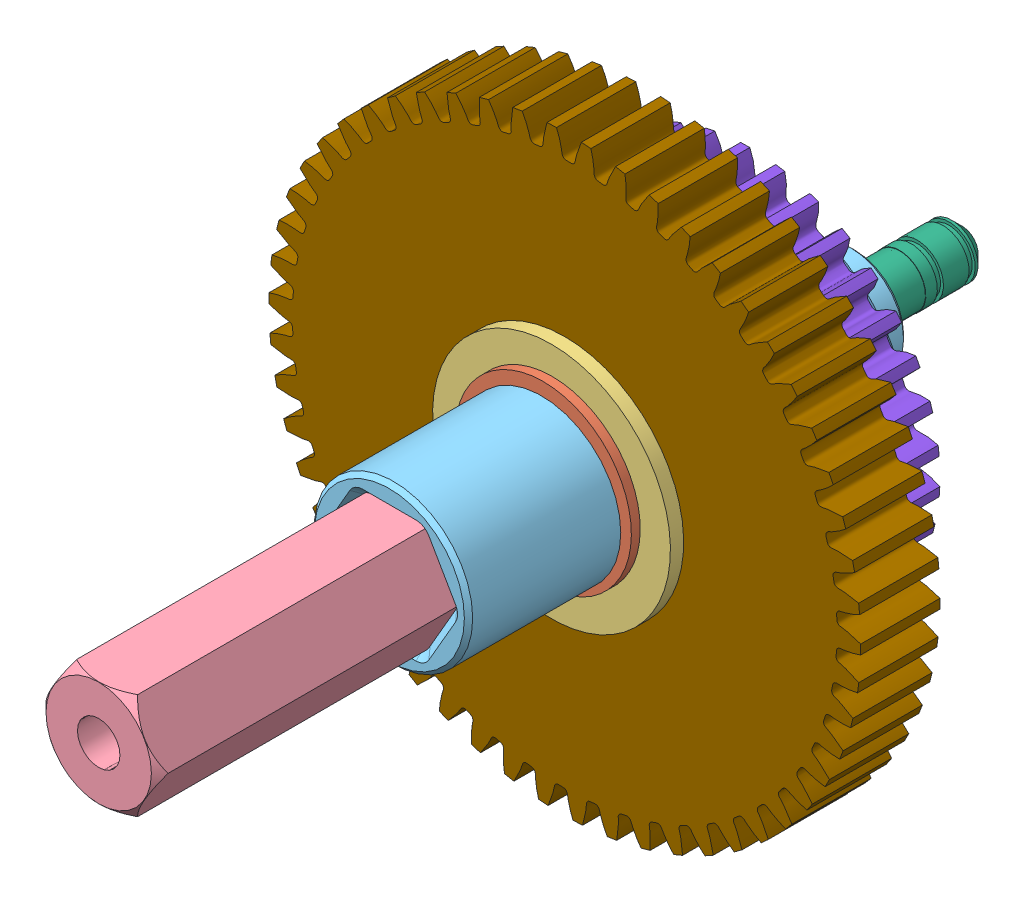
SolidWorks assembly 217-3291-STEP, configuration Default. Lengths in mm.
Overall size (93.31 93.34 103.75).
18 component instances, 9 part files, 0 mates.
Components (placement in the parent):
- 217-2428-008 Rev1-1: 217-2428-008 Rev1 [Default] at (0 0 10.2679) size (31.75 31.75 1.59)
- 217-2428-028 Rev1_97633A250-1: 217-2428-028 Rev1_97633A250 [Default] at (0 0 37.1221) x (0 0 1) z (0.9357 -0.352797 0) size (1.07 23.39 21.18)
- 217-2709-101 Rev1-1: 217-2709-101 Rev1 [Default] at (0 0 20.7137) x (-0.338464 -0.940979 0) z (0 0 -1) size (28.57 28.57 6.1)
  - 217-2428-022 Rev1-1: 217-2428-022 Rev1 [Default] at origin size (28.57 28.57 6.1)
- 217-2713-101 Rev1-1: 217-2713-101 Rev1 [Default] at (0 0 33.4137) x (0.847823 -0.530279 0) z (0 0 -1) size (28.57 28.57 6.1)
  - 217-2428-022 Rev1-1: 217-2428-022 Rev1 [Default] at origin size (28.57 28.57 6.1)
- 217-2790-001 Rev2-1: 217-2790-001 Rev2 [Default] x (-1 0 0) z (0 0 1) size (22.23 22.23 103.75)
  - 217-2790-002 Rev2-1: 217-2790-002 Rev2 [Default] at (0 0 62.9285) x (0 0 1) z (1 0 0) size (55.88 12.7 16.13)
  - 217-2790-003 Rev2-1: 217-2790-003 Rev2 [Default] at origin size (22.23 22.23 55.94)
  - 217-2790-004 Rev2-1: 217-2790-004 Rev2 [Default] at (0 0 26.6866) x (-0.173221 0.984883 0) z (0 0 1) size (11.68 11.68 55)
- 217-2428-007 Rev1-1: 217-2428-007 Rev1 [Default] at (6.3246 0 14.2494) x (0.485433 0.3648 -0.794529) z (-0.690104 -0.398066 -0.6044) size (6.35 6.35 6.35)
- 217-2428-007 Rev1-2: 217-2428-007 Rev1 [Default] at (6.275 0 26.9494) x (0.741485 -0.614816 -0.268704) z (-0.150074 0.23836 -0.959512) size (6.35 6.35 6.35)
- 217-2428-007 Rev1-3: 217-2428-007 Rev1 [Default] at (-3.1623 5.4773 14.2494) x (-0.558642 0.237997 -0.794529) z (0.689788 -0.398615 -0.6044) size (6.35 6.35 6.35)
- 217-2428-007 Rev1-4: 217-2428-007 Rev1 [Default] at (-3.1623 -5.4773 14.2494) x (0.073209 -0.602797 -0.794529) z (0.000317 0.796681 -0.6044) size (6.35 6.35 6.35)
- 217-2428-007 Rev1-5: 217-2428-007 Rev1 [Default] at (-3.1375 5.4343 26.9494) x (0.161703 0.949553 -0.268704) z (-0.131389 -0.249147 -0.959512) size (6.35 6.35 6.35)
- 217-2428-007 Rev1-6: 217-2428-007 Rev1 [Default] at (-3.1375 -5.4343 26.9494) x (-0.903188 -0.334737 -0.268704) z (0.281462 0.010788 -0.959512) size (6.35 6.35 6.35)
- 217-3212-001 Rev1_34t-1: 217-3212-001 Rev1_34t [Default] at (0 0 17.4117) x (0.923728 0.383049 0) z (0 0 -1) size (46.46 46.56 11.11)
- 217-3222-001 Rev1_Spur01-1: 217-3222-001 Rev1_Spur01 [Default] at (0 0 30.1117) x (0.923728 0.383049 0) z (0 0 -1) size (71.39 71.45 11.11)
